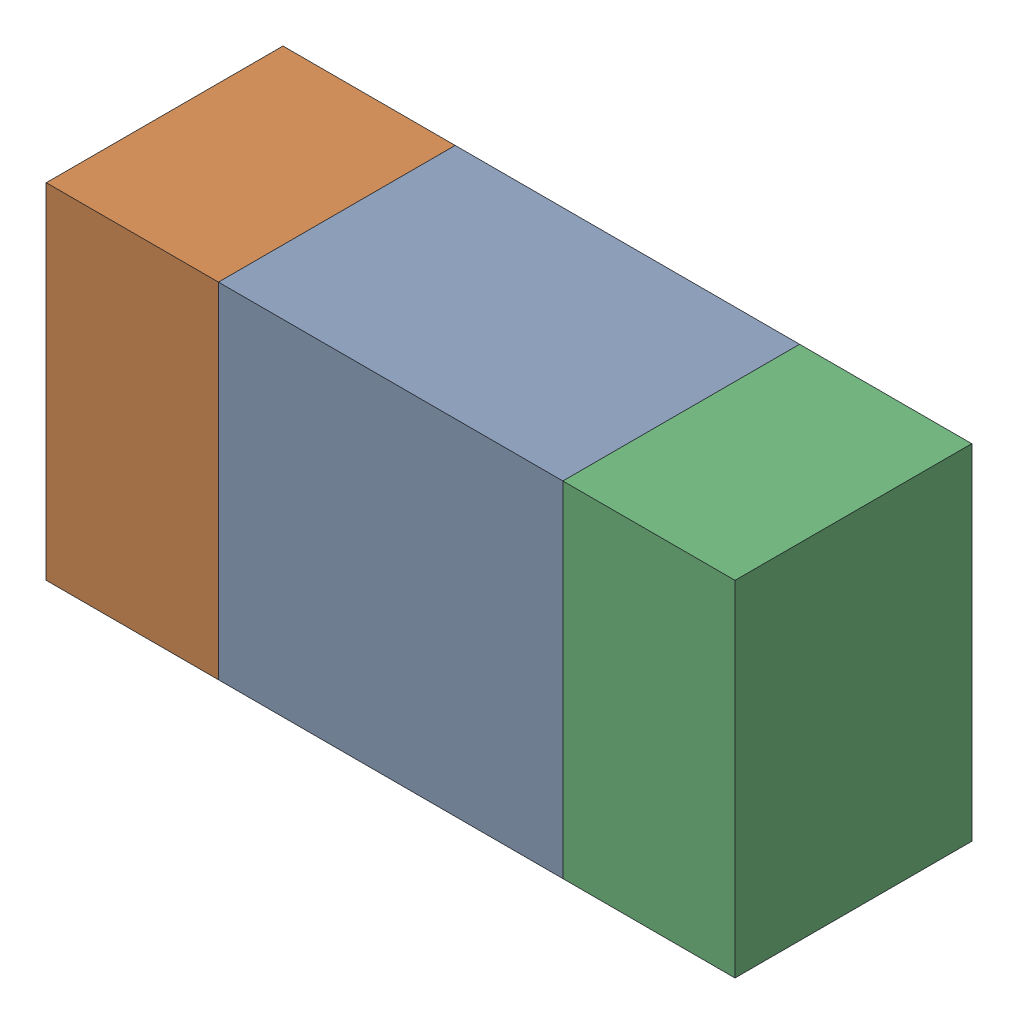
SolidWorks assembly R85, configuration ﾃﾞﾌｫﾙﾄ. Lengths in mm.
Overall size (1.6 0.8 0.55).
6 component instances, 2 part files, 0 mates.
Components (placement in the parent):
- 689261648-1: 689261648 [ﾃﾞﾌｫﾙﾄ] at (16.75 36.4999 0) size (0.8 0.8 0.55)
  - Extruded_33-1: Extruded_33 [ﾃﾞﾌｫﾙﾄ] at origin size (0.8 0.8 0.55)
- 689261512-1: 689261512 [ﾃﾞﾌｫﾙﾄ] at (16.1499 36.4999 0) size (0.4 0.8 0.55)
  - Extruded_32-1: Extruded_32 [ﾃﾞﾌｫﾙﾄ] at origin size (0.4 0.8 0.55)
- 689261512-2: 689261512 [ﾃﾞﾌｫﾙﾄ] at (17.3499 36.4999 0) size (0.4 0.8 0.55)
  - Extruded_32-1: Extruded_32 [ﾃﾞﾌｫﾙﾄ] at origin size (0.4 0.8 0.55)
